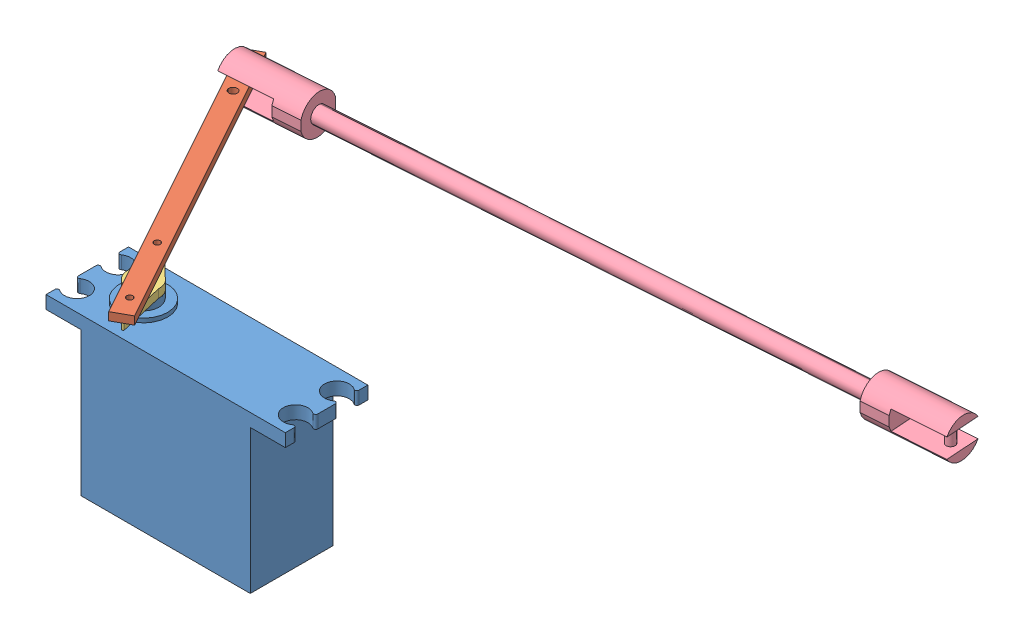
SolidWorks assembly SteeringServo, configuration Default. Lengths in mm.
4 component instances, 4 part files, 7 mates.
Components (placement in the parent):
- Servo-1: Servo [Default] at (29.6042 21.3424 46.3862) size (58 43 20)
- ServoArm-1: ServoArm [Default] at (20.7556 46.3165 48.2034) x (-0.875344 0 0.483501) z (-0.483501 0 -0.875344) size (4.6 1.95 94.1)
- ServoHead-1: ServoHead [Default] at (14.2284 43.3424 36.3862) x (-0.875344 0 0.483501) z (-0.483501 0 -0.875344) size (7.62 2 25.64)
- ServoRod-1: ServoRod [Default] at (127.0859 44.9395 -28.6344) x (0.069362 0 0.997592) z (-0.997592 0 0.069362) size (9.07 9.38 135.13)
Mates (geometry in assembly coordinates):
- Concentric1: concentric aligned: cylinder of Servo-1 through (14.2284 45.3424 36.3862) axis (0 -1 0) radius 1.5; cylinder of ServoHead-1 through (14.2284 45.3424 36.3862) axis (0 -1 0) radius 1.5
- Coincident3: coincident anti-aligned: plane of Servo-1 through (14.2284 43.3424 36.3862) normal (0 1 0); plane of ServoHead-1 through (14.2284 43.3424 36.3862) normal (0 -1 0)
- Concentric2: concentric aligned: cylinder of ServoArm-1 through (18.3381 43.8165 43.8267) axis (0 1 0) radius 0.75; cylinder of ServoHead-1 through (18.3381 41.221 43.8267) axis (0 1 0) radius 0.75
- Concentric3: concentric aligned: cylinder of ServoArm-1 through (10.1186 43.8165 28.9458) axis (0 1 0) radius 0.75; cylinder of ServoHead-1 through (10.1186 41.221 28.9458) axis (0 1 0) radius 0.75
- Concentric4: concentric anti-aligned: cylinder of ServoArm-1 through (-16.1839 43.8165 -18.6729) axis (0 1 0) radius 1.0227; cylinder of ServoRod-1 through (-16.1839 50.373 -18.6729) axis (0 -1 0) radius 1.0898
- Coincident7: coincident anti-aligned: plane of ServoArm-1 through (-20.6168 45.3424 -21.9364) normal (0 -1 0); plane of ServoHead-1 through (14.2284 45.3424 36.3862) normal (0 1 0)
- Coincident8: coincident anti-aligned: plane of ServoArm-1 through (-20.6168 47.2906 -21.9364) normal (0 1 0); plane of ServoRod-1 through (-19.1803 47.2906 -23.0097) normal (0 -1 0)
